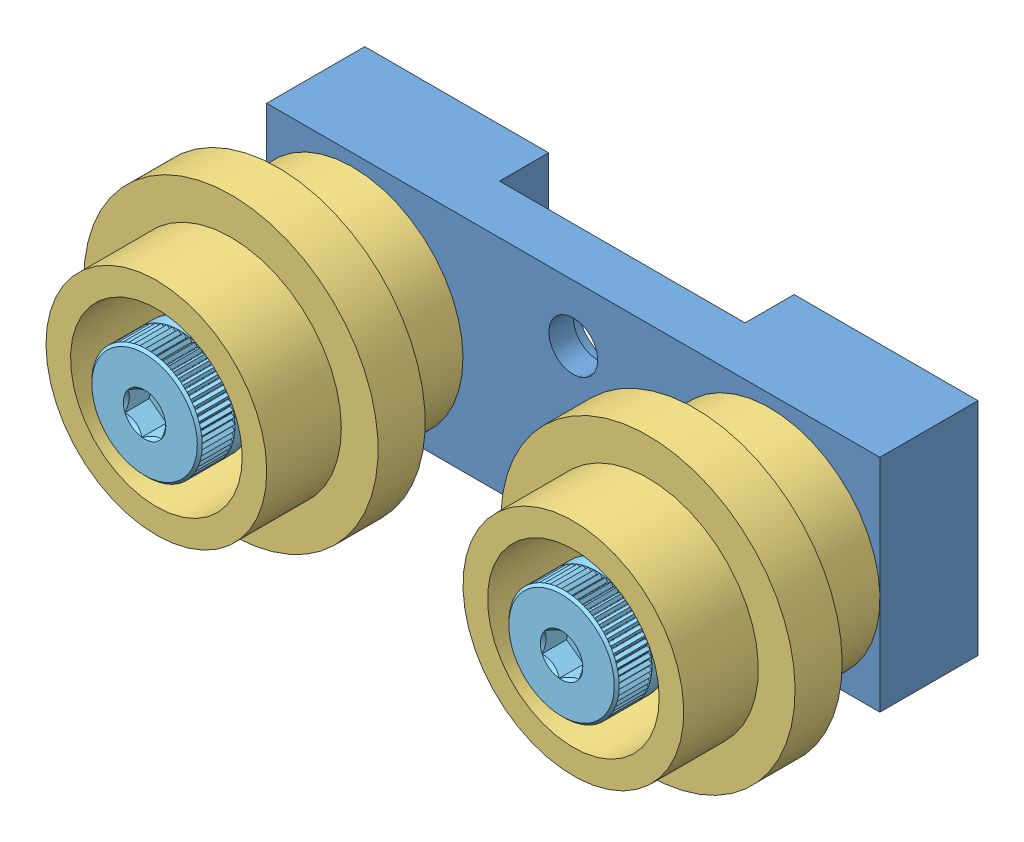
SolidWorks assembly 2018-505-A, configuration Default. Lengths in mm.
Overall size (103.45 50.66 41.78).
9 component instances, 5 part files, 16 mates.
Components (placement in the parent):
- 2018-505-D001-1: 2018-505-D001 [Default] at origin size (79.38 28.57 12.7)
- 2018-505-D003-1: 2018-505-D003 [Default] at (-26.9875 14.2875 0) x (1 0 0) z (0 -1 0) size (22.23 1.57 22.23)
- 2018-505-D003-2: 2018-505-D003 [Default] at (26.9875 14.2875 0) x (-0.292387 0.9563 0) z (0.9563 0.292387 0) size (22.23 1.57 22.23)
- 2018-505-D002-1: 2018-505-D002 [Default] at (-26.9875 14.2875 1.5748) x (0.905661 0.424002 0) z (0 0 -1) size (38.1 38.1 25.4)
- 2018-505-D002-2: 2018-505-D002 [Default] at (26.9875 14.2875 1.5748) x (-0.947338 -0.320235 0) z (0 0 -1) size (38.1 38.1 25.4)
- 2018-505-D004-2: 2018-505-D004 [60355K45] at (26.9875 14.2875 5.1467) x (-1 0 0) z (0 0 -1) size (22.23 22.23 7.14)
- 2018-505-D005-1: 2018-505-D005 [91259A623] at (-26.9875 14.2875 22.1519) x (0.383049 -0.923728 0) z (-0.923728 -0.383049 0) size (14.29 41.78 14.29)
- 2018-505-D005-2: 2018-505-D005 [91259A623] at (26.9875 14.2875 22.1519) x (0.401074 -0.916046 0) z (-0.916046 -0.401074 0) size (14.29 41.78 14.29)
- 2018-505-D004-5: 2018-505-D004 [60355K45] at (-26.9875 14.2875 5.1467) x (-0.923728 -0.383049 0) z (0 0 1) size (22.23 22.23 7.14)
Mates (geometry in assembly coordinates):
- Coincident30: coordinate: point of 2018-505-D001-1; point of assembly
- Coincident31: coincident anti-aligned: plane of 2018-505-D003-2 through (26.9875 14.2875 1.5748) normal (0 0 1); plane of 2018-505-D004-2 through (26.9875 25.0428 1.5748) normal (0 0 -1)
- Concentric15: concentric aligned: cylinder of 2018-505-D003-2 through (26.9875 14.2875 1.5748) axis (0 0 -1) radius 11.1125; cylinder of 2018-505-D004-2 through (26.9875 14.2875 1.5748) axis (0 0 -1) radius 11.1125
- Coincident34: coincident: plane of 2018-505-D005-1 through (-26.9875 14.2875 28.5019) normal (0 0 1); plane of 2018-505-D005-2 through (26.9875 14.2875 28.5019) normal (0 0 1)
- Concentric16: concentric anti-aligned: cylinder of 2018-505-D005-1 through (-26.9875 14.2875 22.1519) axis (0 0 -1) radius 4.7625; cylinder of 2018-505-D004-5 through (-26.9875 14.2875 8.7186) axis (0 0 1) radius 4.7625
- Concentric17: concentric anti-aligned: cylinder of 2018-505-D003-1 through (-26.9875 14.2875 1.5748) axis (0 0 -1) radius 11.1125; cylinder of 2018-505-D004-5 through (-26.9875 14.2875 8.7186) axis (0 0 1) radius 11.1125
- Coincident35: coincident anti-aligned: plane of 2018-505-D001-1 through (-39.6875 28.575 0) normal (0 0 1); plane of 2018-505-D003-1 through (-26.9875 14.2875 0) normal (0 0 -1)
- Concentric18: concentric aligned: cylinder of 2018-505-D001-1 through (-26.9875 14.2875 -12.7) axis (0 0 -1) radius 3.2639; cylinder of 2018-505-D003-1 through (-26.9875 14.2875 1.5748) axis (0 0 -1) radius 4.9784
- Coincident36: coincident anti-aligned: plane of 2018-505-D003-1 through (-26.9875 14.2875 1.5748) normal (0 0 1); plane of 2018-505-D004-5 through (-22.8677 4.3525 1.5748) normal (0 0 -1)
- Concentric19: concentric aligned: cylinder of 2018-505-D004-2 through (26.9875 14.2875 1.5748) axis (0 0 -1) radius 4.7625; cylinder of 2018-505-D005-2 through (26.9875 14.2875 22.1519) axis (0 0 -1) radius 4.7625
- Concentric20: concentric aligned: cylinder of 2018-505-D001-1 through (26.9875 14.2875 -12.7) axis (0 0 -1) radius 3.2639; cylinder of 2018-505-D003-2 through (26.9875 14.2875 1.5748) axis (0 0 -1) radius 4.9784
- Concentric21: concentric anti-aligned: cylinder of 2018-505-D002-2 through (26.9875 14.2875 14.9098) axis (0 0 1) radius 11.1125; cylinder of 2018-505-D005-2 through (26.9875 14.2875 22.1519) axis (0 0 -1) radius 4.7625
- Concentric22: concentric aligned: cylinder of 2018-505-D002-1 through (-26.9875 14.2875 52.3748) axis (0 0 1) radius 5.0419; cylinder of 2018-505-D005-1 through (-26.9875 14.2875 22.1519) axis (0 0 -1) radius 4.7625
- Coincident38: coincident anti-aligned: plane of 2018-505-D001-1 through (-39.6875 28.575 0) normal (0 0 1); plane of 2018-505-D003-2 through (26.9875 14.2875 0) normal (0 0 -1)
- Coincident39: coincident anti-aligned: plane of 2018-505-D003-2 through (26.9875 14.2875 1.5748) normal (0 0 1); plane of 2018-505-D002-2 through (26.9875 14.2875 1.5748) normal (0 0 -1)
- Coincident40: coincident aligned: plane of 2018-505-D002-1 through (-20.9296 1.3479 26.9748) normal (0 0 1); plane of 2018-505-D002-2 through (22.4121 27.8226 26.9748) normal (0 0 1)
